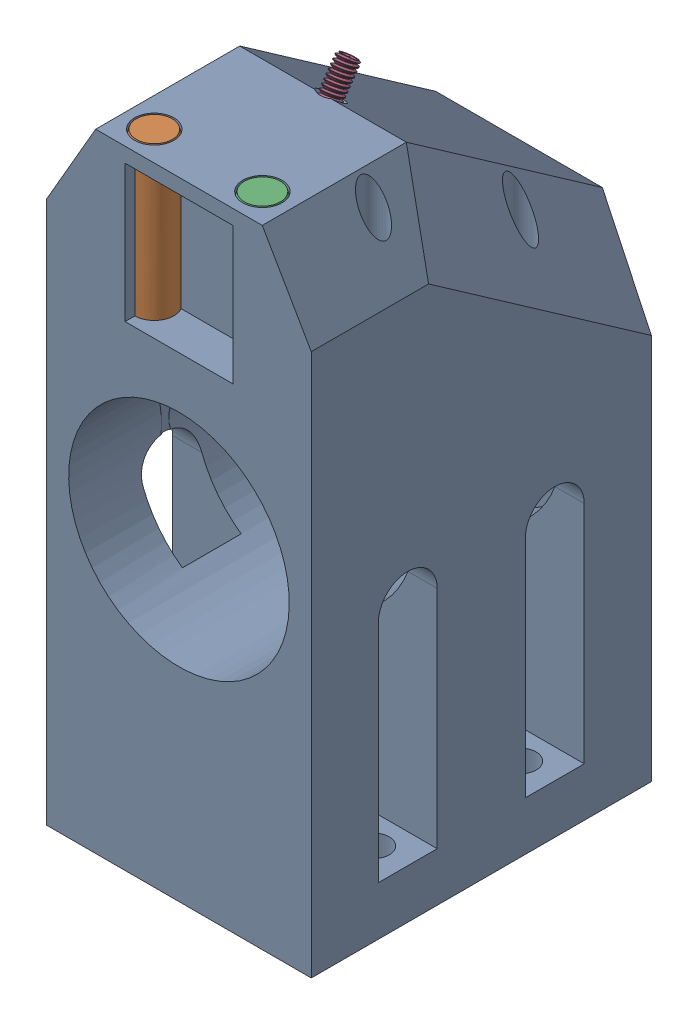
SolidWorks assembly back_coupling_plate_with_inserts, configuration Default. Lengths in mm.
Overall size (27 66.86 34.7).
4 component instances, 3 part files, 0 mates.
Components (placement in the parent):
- bed_coupling_back_plate-1: bed_coupling_back_plate [Default] at (-385.3889 15 -34.7) x (-1 0 0) z (0 1 0) size (27 34.7 64)
- dowel_pin_4mm_d_20mm_l_91585A457_91585A457-1: dowel_pin_4mm_d_20mm_l_91585A457_91585A457 [Default] at (-404.405 54 -3) x (0 -1 0) z (-0.622027 0 0.782996) size (20 4 4)
- dowel_pin_4mm_d_20mm_l_91585A457_91585A457-2: dowel_pin_4mm_d_20mm_l_91585A457_91585A457 [Default] at (-393.3729 54 -3) x (0 -1 0) z (-0.518504 0 0.855075) size (20 4 4)
- m2_set_screw_6mm_92015A093_92015A093-1: m2_set_screw_6mm_92015A093_92015A093 [Default] at (-398.8889 63.7251 -15.7283) x (0.893299 -0.257801 -0.368178) z (0 0.819152 -0.573576) size (2.02 2.05 6.05)
